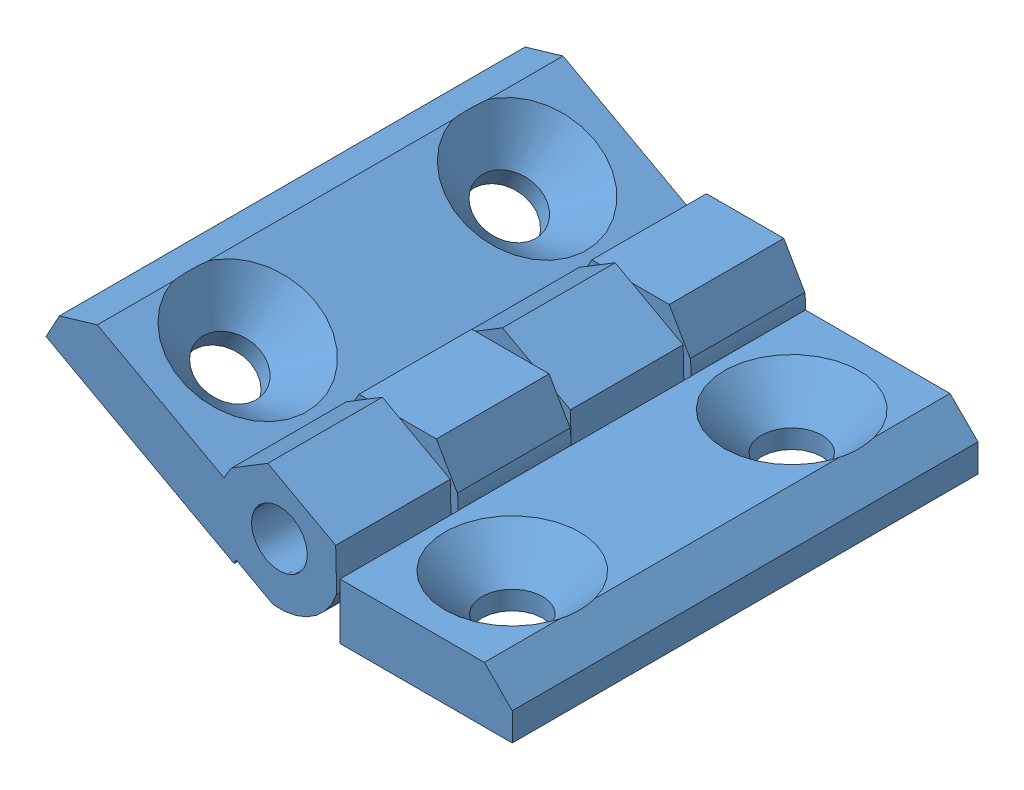
SolidWorks assembly Dobradiça, configuration Default. Lengths in mm.
Overall size (50.06 25.19 50).
2 component instances, 1 part files, 3 mates.
Components (placement in the parent):
- Part21-1: Part21 [Default] at (-42.9452 4.4682 15.2544) size (31.5 11.5 50)
- Part21-2: Part21 [Default] at (-42.9452 4.4682 15.2544) x (-0.877772 0.479078 0) z (0 0 -1) size (31.5 11.5 50)
Mates (geometry in assembly coordinates):
- Concentric1: concentric anti-aligned: cylinder of Part21-1 through (-42.9452 4.4682 40.2544) axis (0 0 -1) radius 3; cylinder of Part21-2 through (-42.9452 4.4682 -9.7456) axis (0 0 1) radius 3
- Coincident1: coincident aligned: plane of Part21-1 through (-42.9452 4.4682 40.2544) normal (0 0 1); plane of Part21-2 through (-42.9452 4.4682 40.2544) normal (0 0 1)
- LimitAngle1: limit planar angle = 0.499604 rad aligned: plane of Part21-1 through (-17.9452 -2.0318 40.2544) normal (0 -1 0); plane of Part21-2 through (-68.0035 10.7397 -9.7456) normal (-0.479078 -0.877772 0)
